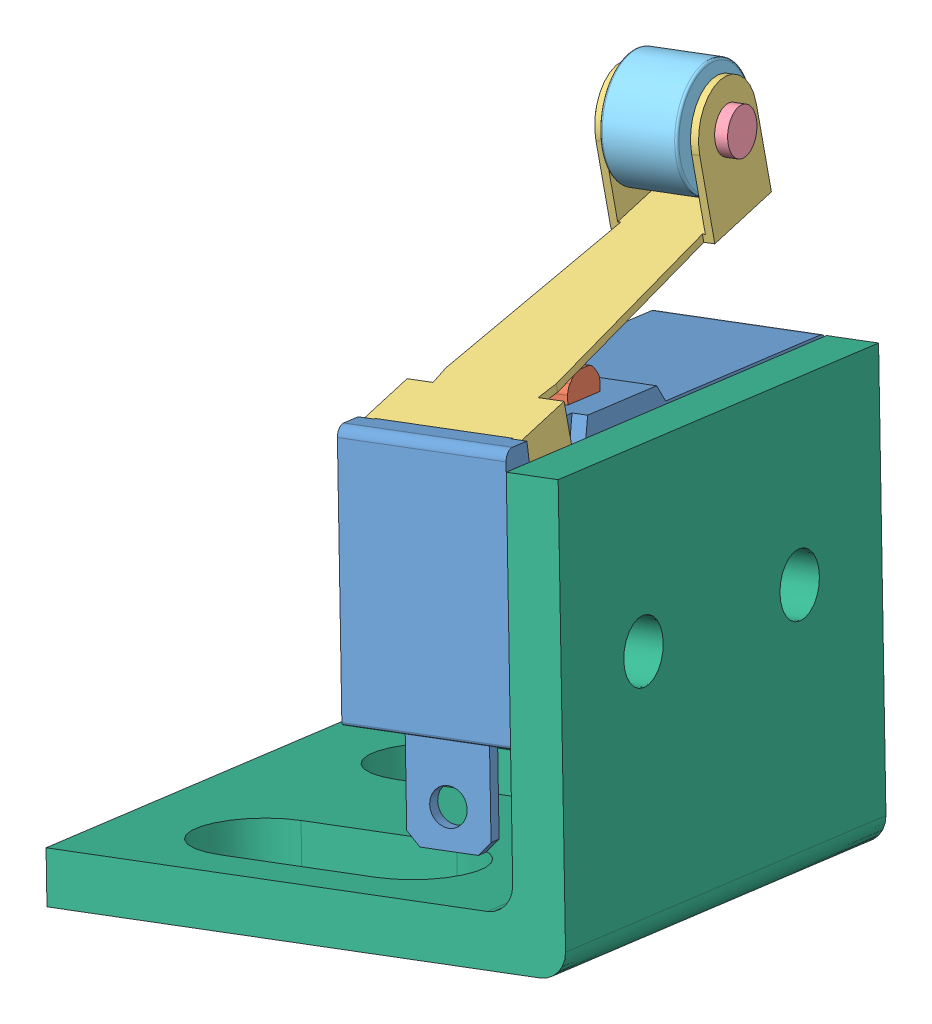
SolidWorks assembly Limit Switch, configuration Default. Lengths in mm.
Overall size (27.13 30.26 27.74).
6 component instances, 6 part files, 12 mates.
Components (placement in the parent):
- Body-1: Body [Default] at (4.2128 20.0017 30.1415) x (-0.191811 -0.289184 -0.93786) z (0.947033 0.196246 -0.254199) size (19.88 14.3 6.9)
- Switch_Button-1: Switch_Button [Default] at (6.7398 15.8798 23.5886) x (-0.191811 -0.289184 -0.93786) z (0.947033 0.196246 -0.254199) size (2 4 4)
- Link-1: Link [Default] at (7.1632 19.9456 28.3046) x (-0.251507 -0.038948 -0.967072) z (0.947033 0.196246 -0.254199) size (18.04 8.82 6.05)
- Wheel shaft-1: Wheel shaft [Default] at (0.0123 22.0471 13.3177) x (-0.211311 0.976858 -0.033099) z (0.947033 0.196246 -0.254199) size (1.82 1.82 5.1)
- Wheel-1: Wheel [Default] at (1.0115 22.2542 13.0496) x (-0.204866 -0.240377 -0.948814) z (0.947033 0.196246 -0.254199) size (4.67 4.67 2.99)
- GaCTHanhTrinh-1: GaCTHanhTrinh [Default] at (0.9968 -1.9027 16.3561) x (0.257561 -0.936942 0.236225) z (-0.947033 -0.196246 0.254199) size (17 19.88 20)
Mates (geometry in assembly coordinates):
- Coincident1: coincident anti-aligned: plane of Body-1 through (8.5772 17.4655 23.7901) normal (-0.947033 -0.196246 0.254199); plane of Switch_Button-1 through (7.7954 20.3093 23.0731) normal (0.947033 0.196246 -0.254199)
- Coincident2: coincident anti-aligned: plane of Body-1 through (4.4054 16.1022 22.9312) normal (0.191811 0.289184 0.93786); plane of Switch_Button-1 through (3.6237 18.9459 22.2142) normal (-0.191811 -0.289184 -0.93786)
- Concentric1: concentric aligned: cylinder of Body-1 through (9.7328 18.2615 26.1531) axis (0.947033 0.196246 -0.254199) radius 0.55; cylinder of Link-1 through (-0.3294 16.1764 28.8539) axis (0.947033 0.196246 -0.254199) radius 0.65
- Tangent1: tangent anti-aligned: cylinder of Switch_Button-1 through (5.8945 19.2438 23.0365) axis (0.947033 0.196246 -0.254199) radius 0.5; plane of Link-1 through (7.1632 19.9456 28.3046) normal (0.199684 -0.979781 -0.012472)
- Symmetric1: symmetric aligned: plane of Body-1 through (0.7442 13.394 12.1176) normal (-0.947033 -0.196246 0.254199); plane of Body-1 through (6.8999 14.6696 10.4653) normal (0.947033 0.196246 -0.254199); plane of Link-1 through (7.1632 19.9456 28.3046) normal (0.947033 0.196246 -0.254199)
- Concentric2: concentric aligned: cylinder of Link-1 through (5.0979 23.101 11.9527) axis (-0.947033 -0.196246 0.254199) radius 0.75; cylinder of Wheel shaft-1 through (4.8422 23.048 12.0213) axis (-0.947033 -0.196246 0.254199) radius 0.5
- Symmetric2: symmetric aligned: plane of Link-1 through (7.1632 19.9456 28.3046) normal (0.947033 0.196246 -0.254199); plane of Wheel shaft-1 through (4.8422 23.048 12.0213) normal (0.947033 0.196246 -0.254199); plane of Wheel shaft-1 through (0.0123 22.0471 13.3177) normal (-0.947033 -0.196246 0.254199)
- Concentric3: concentric aligned: cylinder of Wheel shaft-1 through (4.8422 23.048 12.0213) axis (-0.947033 -0.196246 0.254199) radius 0.5; cylinder of Wheel-1 through (3.8431 22.8409 12.2895) axis (-0.947033 -0.196246 0.254199) radius 0.6
- Symmetric3: symmetric aligned: plane of Link-1 through (7.1632 19.9456 28.3046) normal (0.947033 0.196246 -0.254199); plane of Wheel-1 through (3.8431 22.8409 12.2895) normal (0.947033 0.196246 -0.254199); plane of Wheel-1 through (1.0115 22.2542 13.0496) normal (-0.947033 -0.196246 0.254199)
- Concentric4: concentric anti-aligned: cylinder of Body-1 through (0.0584 7.778 18.9957) axis (0.947033 0.196246 -0.254199) radius 1.225; cylinder of GaCTHanhTrinh-1 through (11.4227 10.1329 15.9453) axis (-0.947033 -0.196246 0.254199) radius 1.225
- Concentric5: concentric anti-aligned: cylinder of Body-1 through (1.917 10.5802 28.0835) axis (0.947033 0.196246 -0.254199) radius 1.225; cylinder of GaCTHanhTrinh-1 through (13.2814 12.9351 25.0331) axis (-0.947033 -0.196246 0.254199) radius 1.225
- Coincident3: coincident anti-aligned: plane of Body-1 through (6.8999 14.6696 10.4653) normal (0.947033 0.196246 -0.254199); plane of GaCTHanhTrinh-1 through (14.6024 5.8755 32.3723) normal (-0.947033 -0.196246 0.254199)
